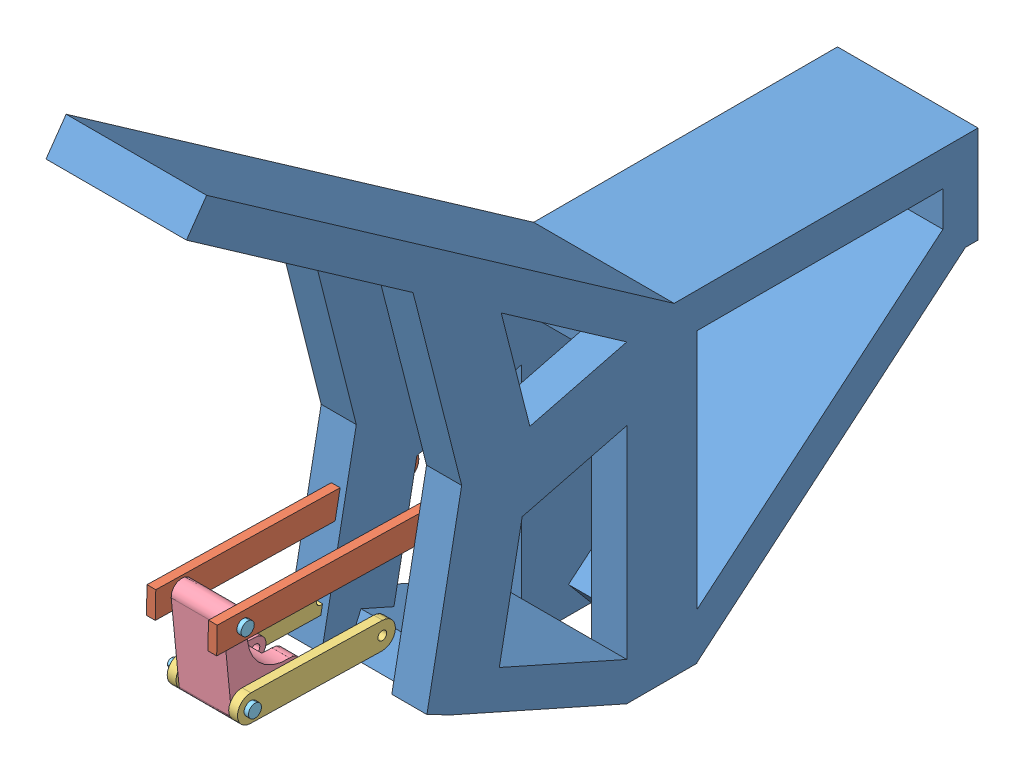
SolidWorks assembly сборка(не завершённая), configuration По умолчанию. Lengths in mm.
Overall size (160 740.82 901.47).
8 component instances, 5 part files, 10 mates.
Components (placement in the parent):
- Рама 1-1: Рама 1 [По умолчанию] at origin size (160 740.82 901.47)
- Рычаг подвески 1-1: Рычаг подвески 1 [По умолчанию] at (-10.9563 -110.147 524.4388) x (1 0 0) z (0 0.021086 0.999778) size (10 30 300)
- Рычаг подвески 1-2: Рычаг подвески 1 [По умолчанию] at (59.0437 -110.147 524.4388) x (1 0 0) z (0 0.021086 0.999778) size (10 30 300)
- Рычач подвески 2-1: Рычач подвески 2 [По умолчанию] at (-42.3987 -190.4581 751.5007) x (1 0 0) z (0 0.022404 0.999749) size (10 30 180)
- Рычач подвески 2-2: Рычач подвески 2 [По умолчанию] at (27.6013 -190.4581 751.5007) x (1 0 0) z (0 0.022404 0.999749) size (10 30 180)
- Рычаг родвески 3-1: Рычаг родвески 3 [По умолчанию] at (20.7494 -186.8948 769.8271) x (0 0.097294 -0.995256) z (1 0 0) size (80 109.83 60)
- ось 1-1: ось 1 [По умолчанию] at (69.8184 -215.8154 741.3303) x (0 1 0) z (0 0 1) size (15 95 15)
- ось 1-2: ось 1 [По умолчанию] at (69.8184 -130.5666 749.664) x (0 1 0) z (0 0 1) size (15 95 15)
Mates (geometry in assembly coordinates):
- Совпадение3: coincident aligned: circle of Рама 1-1; circle of Рычаг подвески 1-1
- Совпадение4: coincident anti-aligned: circle of Рама 1-1; circle of Рычаг подвески 1-2
- Совпадение11: coincident anti-aligned: circle of Рама 1-1; circle of Рычач подвески 2-2
- Совпадение10: coincident aligned: circle of Рама 1-1; circle of Рычач подвески 2-1
- Совпадение8: coincident aligned: circle of Рычач подвески 2-2; circle of Рычаг родвески 3-1
- Совпадение12: coincident aligned: circle of Рычаг подвески 1-1; circle of Рычаг родвески 3-1
- Совпадение13: coincident aligned: circle of Рычач подвески 2-1; circle of Рычаг родвески 3-1
- Совпадение14: coincident aligned: circle of Рычаг подвески 1-2; circle of Рычаг родвески 3-1
- Совпадение15: coincident anti-aligned: circle of Рычач подвески 2-2; circle of ось 1-1
- Совпадение16: coincident anti-aligned: circle of Рычаг подвески 1-2; circle of ось 1-2
